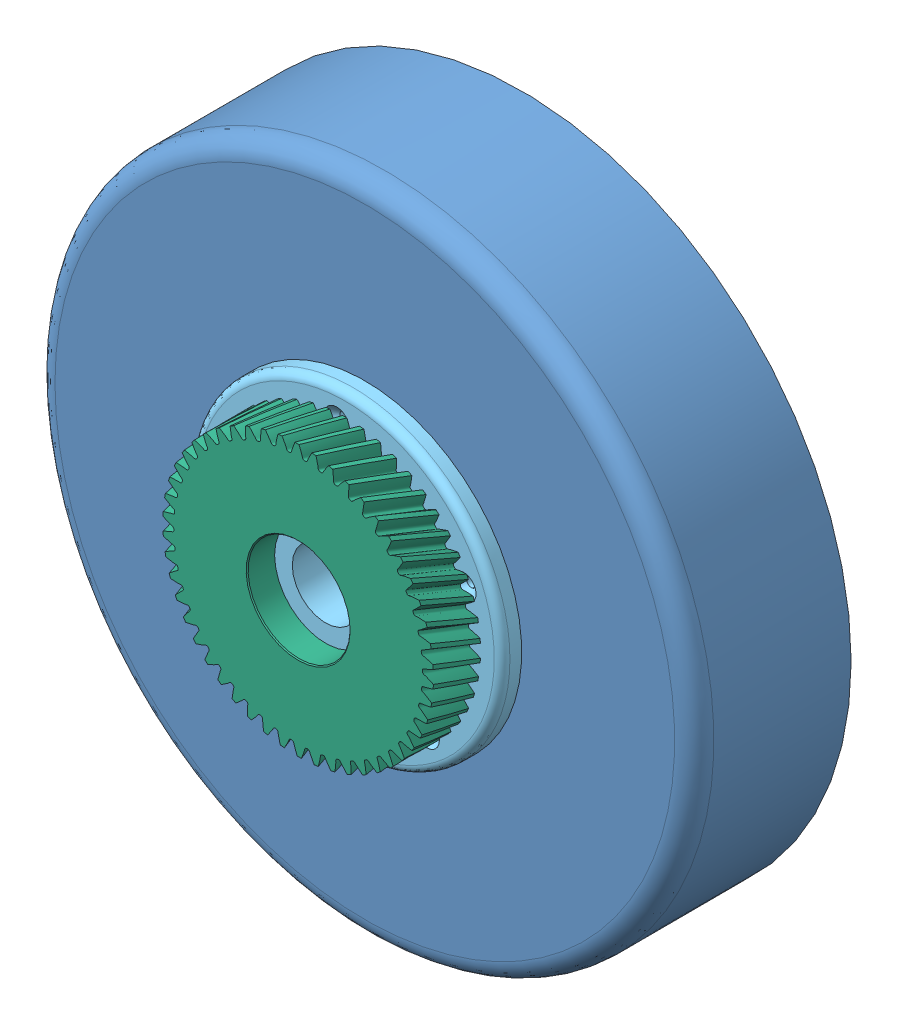
SolidWorks assembly Sun_Motor_Assembly, configuration Default. Lengths in mm.
Overall size (168 168 57).
8 component instances, 6 part files, 5 mates.
Components (placement in the parent):
- Motor_assembly_rev1-1: Motor_assembly_rev1 [Default] at (46.357 91.228 140.4438) size (168 168 40)
  - Motor_cover_rev1-1: Motor_cover_rev1 [Default] at (-15.6766 35.7639 69.6895) x (0 0 -1) z (1 0 0) size (40 168 168)
  - Motor_stator-1: Motor_stator [Default] at (-15.6766 90.7639 49.6895) x (0 0 1) z (-1 0 0) size (20 160 160)
  - Motor_circuit_board-1: Motor_circuit_board [Default] at (-15.6766 35.7639 41.6895) size (80 120 8)
  - Motor_Rotor_rev1-2: Motor_Rotor_rev1 [Default] at (-15.6766 35.7639 49.6895) x (0.939385 -0.342865 0) z (0 0 1) size (108 108 20)
- Sun Gear Attachment-1: Sun Gear Attachment [Default] at (46.357 91.228 145.4438) size (80.92 80.87 17)
  - Attachment Detail-1: Attachment Detail [Default] at (-15.6766 35.7639 77.1895) size (80 80 10)
  - Sun 50t-1: Sun 50t [Sun_Driver01] at (-15.6766 35.7639 85.6895) x (0.184269 0.982876 0) z (0 0 -1) size (69.28 69.34 12)
Mates (geometry in assembly coordinates):
- Concentric1: concentric: cylinder of Motor_assembly_rev1-1/Motor_cover_rev1-1 through (30.6805 126.9919 180.1332) axis (0 0 1) radius 11; cylinder of Sun Gear Attachment-1/Attachment Detail-1 through (30.6805 126.9919 225.1332) axis (0 0 -1) radius 8.5
- Coincident1: coincident anti-aligned: plane of Motor_assembly_rev1-1/Motor_cover_rev1-1 through (30.6805 126.9919 215.1332) normal (0 0 1); plane of Sun Gear Attachment-1/Attachment Detail-1 through (30.6805 126.9919 215.1332) normal (0 0 -1)
- Concentric2: concentric aligned: cylinder of Motor_assembly_rev1-1/Motor_cover_rev1-1 through (30.6805 159.4919 180.1322) axis (0 0 1) radius 1.2; cylinder of Sun Gear Attachment-1/Attachment Detail-1 through (30.6805 159.4919 220.1332) axis (0 0 1) radius 1.2
- Coincident4: coincident: plane of Motor_assembly_rev1-1/Motor_cover_rev1-1 through (30.6805 210.9919 220.1332) normal (0 0 1); plane of Sun Gear Attachment-1/Attachment Detail-1 through (30.6805 126.9919 220.1332) normal (0 0 -1)
- Coincident9: coincident aligned: plane of Motor_assembly_rev1-1 through (46.357 91.228 140.4438) normal (0 1 0); plane of Sun Gear Attachment-1 through (46.357 91.228 145.4438) normal (0 1 0)
